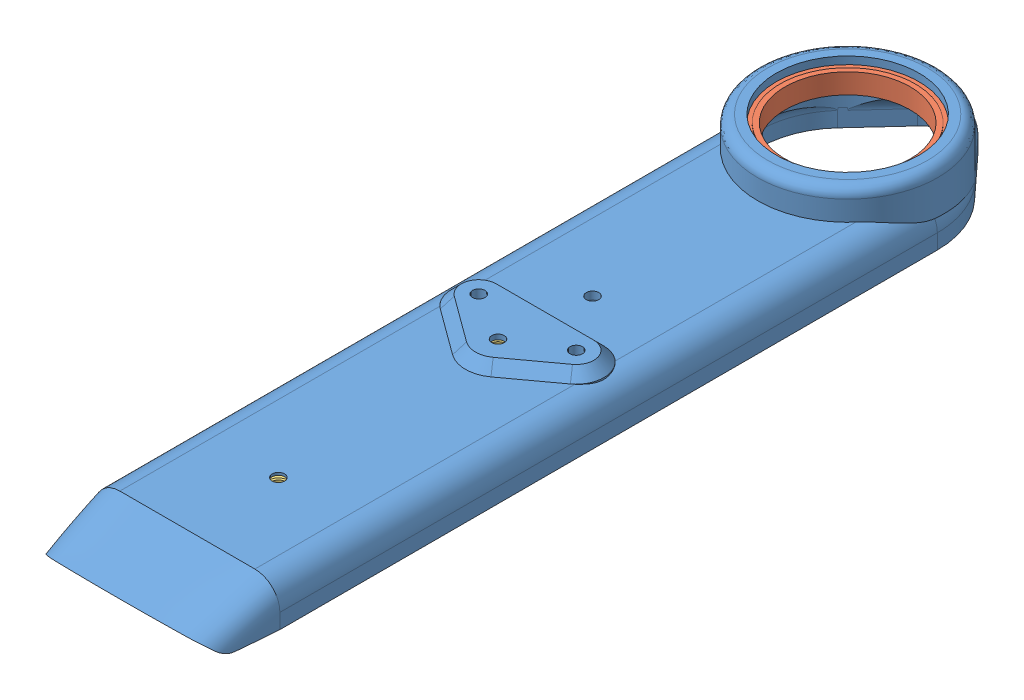
SolidWorks assembly upper limb cover, configuration Default. Lengths in mm.
Overall size (38.63 17.96 170.23).
4 component instances, 3 part files, 6 mates.
Components (placement in the parent):
- upper leg module cover-1: upper leg module cover [Default] at (46.3902 74.2679 138.4484) x (0 0 1) z (-1 0 0) size (170.23 17.96 37.06)
- bearing 32x25x4mm-1: bearing 32x25x4mm [Default] at (46.3902 82.7679 83.8193) x (0.971937 0 0.23524) z (-0.23524 0 0.971937) size (32 4 32)
- bearing 8mm x 3mm x 3mm-1: bearing 8mm x 3mm x 3mm [Default] at (46.3902 80.7679 197.6193) x (0.971329 0 -0.237741) z (0 -1 0) size (7.96 7.96 3)
- bearing 8mm x 3mm x 3mm-2: bearing 8mm x 3mm x 3mm [Default] at (46.3902 82.7679 153.7193) x (0.950519 0 -0.310666) z (0 -1 0) size (7.96 7.96 3)
Mates (geometry in assembly coordinates):
- Concentric1: concentric anti-aligned: cylinder of upper leg module cover-1 through (46.3902 76.2679 83.8193) axis (0 1 0) radius 16.4954; cylinder of bearing 32x25x4mm-1 through (46.3902 86.7679 83.8193) axis (0 -1 0) radius 16
- Coincident1: coincident anti-aligned: plane of upper leg module cover-1 through (46.3902 86.7679 83.8193) normal (0 -1 0); plane of bearing 32x25x4mm-1 through (46.3902 86.7679 83.8193) normal (0 1 0)
- Concentric2: concentric aligned: cylinder of upper leg module cover-1 through (46.3902 78.7679 197.6193) axis (0 1 0) radius 3.98; cylinder of bearing 8mm x 3mm x 3mm-1 through (46.3902 77.7679 197.6193) axis (0 1 0) radius 3.98
- Coincident2: coincident anti-aligned: plane of upper leg module cover-1 through (46.3902 80.7679 138.4484) normal (0 -1 0); plane of bearing 8mm x 3mm x 3mm-1 through (46.3902 80.7679 197.6193) normal (0 1 0)
- Concentric3: concentric anti-aligned: cylinder of upper leg module cover-1 through (46.3902 82.7679 153.7193) axis (0 -1 0) radius 3.98; cylinder of bearing 8mm x 3mm x 3mm-2 through (46.3902 79.7679 153.7193) axis (0 1 0) radius 3.98
- Coincident3: coincident anti-aligned: plane of upper leg module cover-1 through (46.3902 82.7679 153.7193) normal (0 -1 0); plane of bearing 8mm x 3mm x 3mm-2 through (46.3902 82.7679 153.7193) normal (0 1 0)
